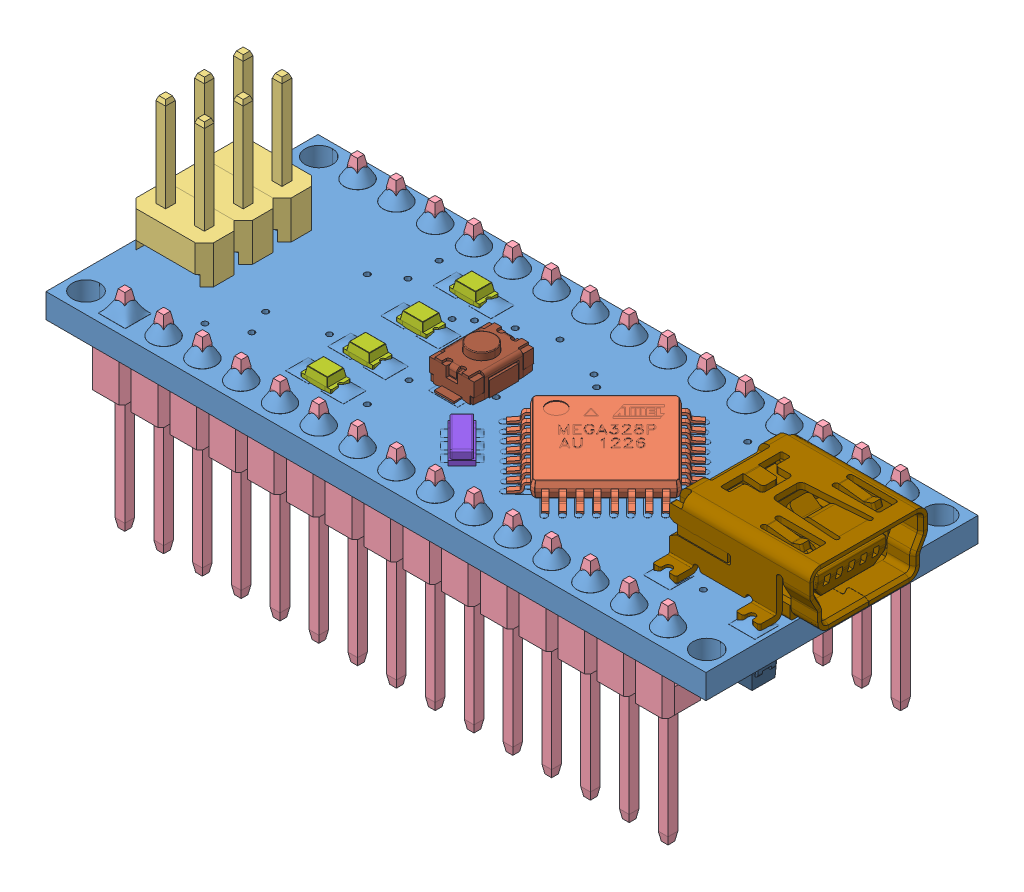
SolidWorks assembly Arduino nano.STEP, configuration Default. Lengths in mm.
Overall size (44.95 20.74 17.81).
26 component instances, 15 part files, 0 mates.
Components (placement in the parent):
- nano board.STEP-1: nano board.STEP [Default] at (-19.4402 -11.2238 15.5223) size (43.2 4.83 17.81)
- atmega328.STEP-1: atmega328.STEP [Default] at (4.4398 -9.5491 7.9045) x (-0.707107 0 0.707107) z (-0.707107 0 -0.707107) size (9.21 1.07 9.21)
- PLD-2.step.STEP-1: PLD-2.step.STEP [Default] at (-19.3102 -9.6238 10.4401) x (0 0 -1) z (0 1 0) size (2.54 5.08 11.6)
- PLD-2.step.STEP-2: PLD-2.step.STEP [Default] at (-21.8502 -9.6238 7.9001) x (0 0 1) z (0 1 0) size (2.54 5.08 11.6)
- PLD-2.step.STEP-3: PLD-2.step.STEP [Default] at (-21.8502 -9.6238 5.3601) x (0 0 1) z (0 1 0) size (2.54 5.08 11.6)
- 1x15 Male Pin Header.STEP-1: 1x15 Male Pin Header.STEP [Default] at (16.1198 -11.2238 15.5201) x (-1 0 0) z (0 0 1) size (38.1 13.54 2.5)
- 1x15 Male Pin Header.STEP-2: 1x15 Male Pin Header.STEP [Default] at (16.1198 -11.2238 0.2988) x (-1 0 0) z (0 0 1) size (38.1 13.54 2.5)
- FTDI FT232RL.STEP-1: FTDI FT232RL.STEP [Default] at (9.5398 -11.4738 7.9545) x (1 0 0) z (0 0 -1) size (10.2 2 7.81)
- User Library-C0805-2.step.STEP-1: User Library-C0805-2.step.STEP [Default] at (2.3498 -11.2238 9.7351) x (-1 0 0) z (0 0 1) size (2 0.8 1.25)
- User Library-C0805-2.step.STEP-2: User Library-C0805-2.step.STEP [Default] at (2.3498 -11.2238 6.4738) x (-1 0 0) z (0 0 1) size (2 0.8 1.25)
- User Library-C0805-2.step.STEP-3: User Library-C0805-2.step.STEP [Default] at (17.2598 -11.2238 3.6138) x (-1 0 0) z (0 0 1) size (2 0.8 1.25)
- User Library-C0805-2.step.STEP-4: User Library-C0805-2.step.STEP [Default] at (17.2598 -11.2238 7.8938) x (-1 0 0) z (0 0 1) size (2 0.8 1.25)
- User Library-C0805-2.step.STEP-5: User Library-C0805-2.step.STEP [Default] at (-11.2302 -11.2238 12.8551) x (-1 0 0) z (0 0 1) size (2 0.8 1.25)
- 0805 Chip SMD LED (2x1.2mm).step.STEP-1: 0805 Chip SMD LED (2x1.2mm).step.STEP [Default] at (-9.0502 -9.6238 3.0738) size (2 0.8 1.25)
- 0805 Chip SMD LED (2x1.2mm).step.STEP-2: 0805 Chip SMD LED (2x1.2mm).step.STEP [Default] at (-9.0502 -9.6238 6.5238) size (2 0.8 1.25)
- 0805 Chip SMD LED (2x1.2mm).step.STEP-3: 0805 Chip SMD LED (2x1.2mm).step.STEP [Default] at (-9.0502 -9.6238 12.7738) size (2 0.8 1.25)
- 0805 Chip SMD LED (2x1.2mm).step.STEP-4: 0805 Chip SMD LED (2x1.2mm).step.STEP [Default] at (-9.0502 -9.6238 10.0238) size (2 0.8 1.25)
- SMD Crystal 16MHz.STEP-1: SMD Crystal 16MHz.STEP [Default] at (-0.8996 -9.8238 12.0012) x (0.707107 0 0.707107) z (-0.707107 0 0.707107) size (3.2 0.8 1.3)
- Mini B USB.STEP-1: Mini B USB.STEP [Default] at (16.9898 -9.6238 7.9545) x (0 0 -1) z (1 0 0) size (9.9 5.06 9.4)
- Tantalum Capacitor 475C A3216.STEP-1: Tantalum Capacitor 475C A3216.STEP [Default] at (17.6998 -11.2238 12.2252) x (1 0 0) z (0 0 -1) size (3.2 1.8 1.6)
- Tantalum Capacitor 475C A3216.STEP-2: Tantalum Capacitor 475C A3216.STEP [Default] at (-11.5202 -11.2238 9.9152) x (-1 0 0) z (0 0 1) size (3.2 1.8 1.6)
- Pushbutton3x4x2.STEP-1: Pushbutton3x4x2.STEP [Default] at (-4.1602 -9.6238 7.4401) x (0 0 1) z (-1 0 0) size (4.9 2 2.9)
- C5 FD10 Reg.STEP-1: C5 FD10 Reg.STEP [Default] at (-13.248 -11.3133 5.3988) x (0 0 -1) z (-1 0 0) size (6.5 1.69 7.02)
- Diode MBR0520.STEP-1: Diode MBR0520.STEP [Default] at (-8.0002 -11.9313 11.2601) x (0 0 1) z (1 0 0) size (3.65 1.45 1.55)
- 102 RESISTOR PACK.STEP-1: 102 RESISTOR PACK.STEP [Default] at (-3.7602 -11.2238 10.3738) x (0 0 1) z (1 0 0) size (3.2 0.46 1.5)
- 189 RESISTOR PACK.STEP-1: 189 RESISTOR PACK.STEP [Default] at (-3.7602 -11.2238 4.7388) x (0 0 1) z (1 0 0) size (3.2 0.46 1.5)
